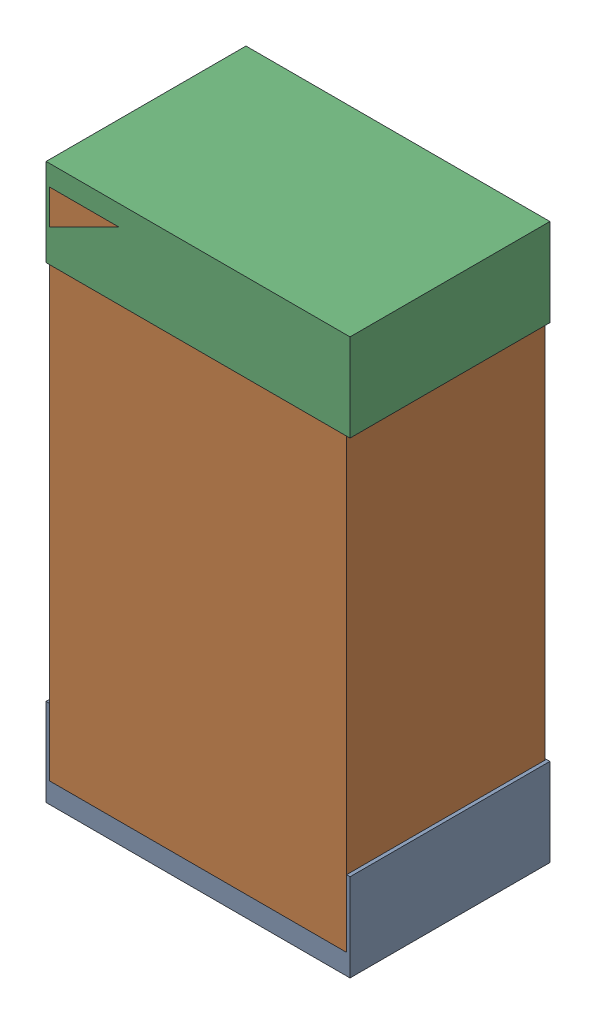
SolidWorks assembly R41Kanaloa_v2.0.0_Motor, configuration Default. Lengths in mm.
Overall size (1.3 2.38 0.85).
6 component instances, 2 part files, 0 mates.
Components (placement in the parent):
- 330415056-1: 330415056 [Default] at (96.52 126.254 -1.9574) size (1.3 0.38 0.85)
  - Extruded_2-1: Extruded_2 [Default] at origin size (1.3 0.38 0.85)
- 334787376-1: 334787376 [Default] at (96.52 127.254 -1.9524) size (1.27 2.2 0.85)
  - Extruded_16-1: Extruded_16 [Default] at origin size (1.27 2.2 0.85)
- 330415056-2: 330415056 [Default] at (96.52 128.254 -1.9574) size (1.3 0.38 0.85)
  - Extruded_2-1: Extruded_2 [Default] at origin size (1.3 0.38 0.85)
